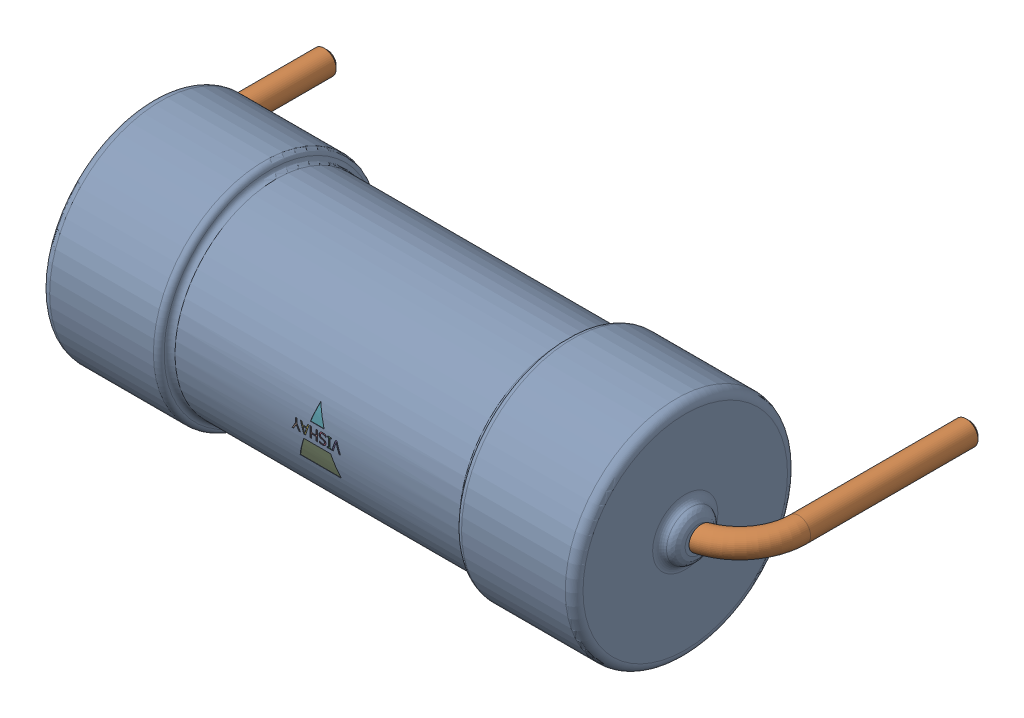
SolidWorks assembly R9.step, configuration Default. Lengths in mm.
Overall size (22.46 7.5 11.5).
4 component instances, 3 part files, 0 mates.
Components (placement in the parent):
- Res_Vishay_AC05000003909JAC00_eec.step-1: Res_Vishay_AC05000003909JAC00_eec.step [Default] at (114.935 71.12 0) x (-1 0 0) z (0 0 1) size (22.46 7.5 11.5)
  - AC0500000XXXJAC00.step-1: AC0500000XXXJAC00.step [Default] at (-37 0 3.75) size (18.87 7.5 7.5)
  - 1-4.step-1: 1-4.step [Default] at (0 0 -8) x (1 0 0) z (0 -1 0) size (22.46 8.15 0.8)
  - 2-5.step-1: 2-5.step [Default] at (-37 0 3.75) size (1.63 1.9 3.41)
